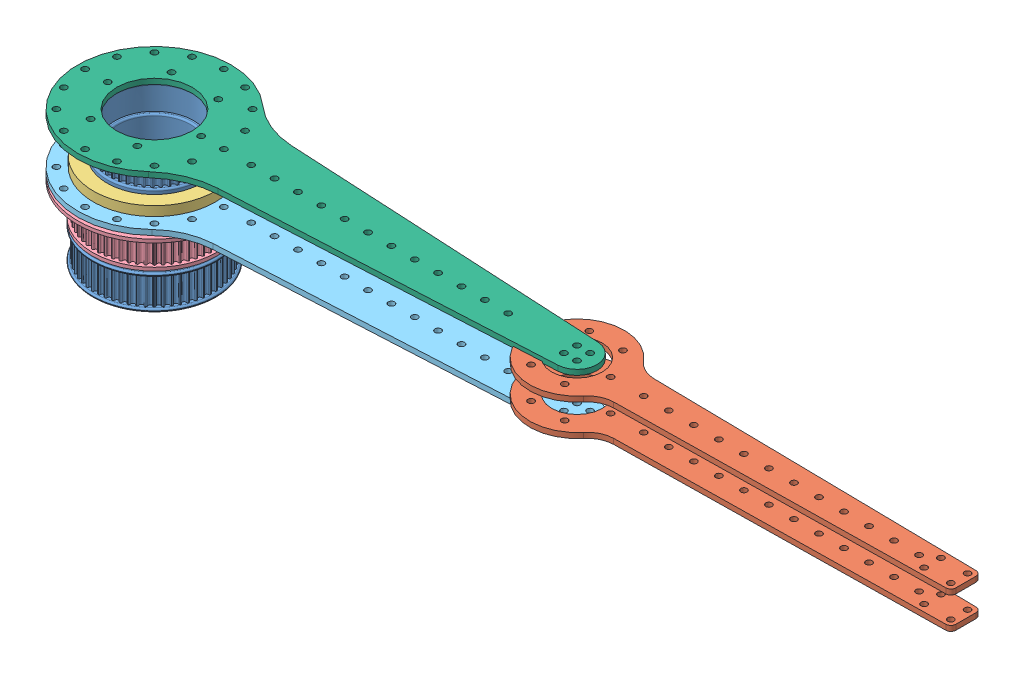
SolidWorks assembly arm rough draft, configuration Default. Lengths in mm.
Overall size (425.77 63.12 79.55).
7 component instances, 6 part files, 10 mates.
Components (placement in the parent):
- 60T 40T htd3mm - Copy-1: 60T 40T htd3mm - Copy [Default] at origin size (58.88 60.62 58.88)
- Carbon Plate Lower Extremedy-1: Carbon Plate Lower Extremedy [Default] at (301 51.95 0) x (-1 0 0) z (0 -1 0) size (207.5 45 2.5)
- Carbon Plate Lower Extremedy-2: Carbon Plate Lower Extremedy [Default] at (301 36.95 0) x (-1 0 0) z (0 -1 0) size (207.5 45 2.5)
- Bearing 45_58_7mm-1: Bearing 45_58_7mm [Default] at (0 32.2425 0) x (0.858187 0 -0.513338) z (0 1 0) size (58 58 7)
- UpperExtremedyDriven 3htd-1: UpperExtremedyDriven 3htd [Default] at (0 17.175 0) x (0 0 -1) z (-1 0 0) size (73.03 18.17 73.03)
- Part2^arm rough draft-1: Part2^arm rough draft [Default] at origin size (247.04 2.5 73.03) (virtual)
- Part3^arm rough draft-1: Part3^arm rough draft [Default] at origin size (247.03 2.5 73) (virtual)
Mates (geometry in assembly coordinates):
- Coincident1: coincident: plane of 60T 40T htd3mm - Copy-1 through (0 44.45 0) normal (0 1 0); plane of Carbon Plate Lower Extremedy-1 through (106.0966 44.45 31.5175) normal (0 -1 0)
- Coincident2: coincident: line of Carbon Plate Lower Extremedy-1 through (2.5 201 50.7) axis (0 0 1)
- Distance3: distance = 201 mm: cylinder of 60T 40T htd3mm - Copy-1 through (0 34.9332 0) axis (0 1 0) radius 23.2937; cylinder of Carbon Plate Lower Extremedy-1 through (201 53.2 0) axis (0 -1 0) radius 12
- Distance4: distance = 12.5 mm anti-aligned: plane of Carbon Plate Lower Extremedy-2 through (401 38.2 0) normal (0 1 0); plane of Carbon Plate Lower Extremedy-1 through (401 50.7 0) normal (0 -1 0)
- Concentric4: concentric anti-aligned: cylinder of 60T 40T htd3mm - Copy-1 through (0 34.9332 0) axis (0 1 0) radius 22.5; cylinder of Bearing 45_58_7mm-1 through (0 35.7425 0) axis (0 -1 0) radius 22.5
- Coincident4: coincident anti-aligned: plane of 60T 40T htd3mm - Copy-1 through (22.5 28.7425 0) normal (0 1 0); plane of Bearing 45_58_7mm-1 through (0 28.7425 0) normal (0 -1 0)
- Concentric5: concentric aligned: cylinder of 60T 40T htd3mm - Copy-1 through (0 34.9332 0) axis (0 1 0) radius 23.2937; cylinder of UpperExtremedyDriven 3htd-1 through (0 9.0875 0) axis (0 1 0) radius 23.8852
- Distance5: distance = 1 mm anti-aligned: plane of 60T 40T htd3mm - Copy-1 through (0 8.0875 0) normal (0 1 0); plane of UpperExtremedyDriven 3htd-1 through (0 9.0875 0) normal (0 -1 0)
- Coincident7: coincident anti-aligned: plane of Carbon Plate Lower Extremedy-1 through (301 51.95 0) normal (0 0 -1)
- Coincident8: coincident anti-aligned: plane of UpperExtremedyDriven 3htd-1 through (0 17.175 0) normal (0 0 -1)
